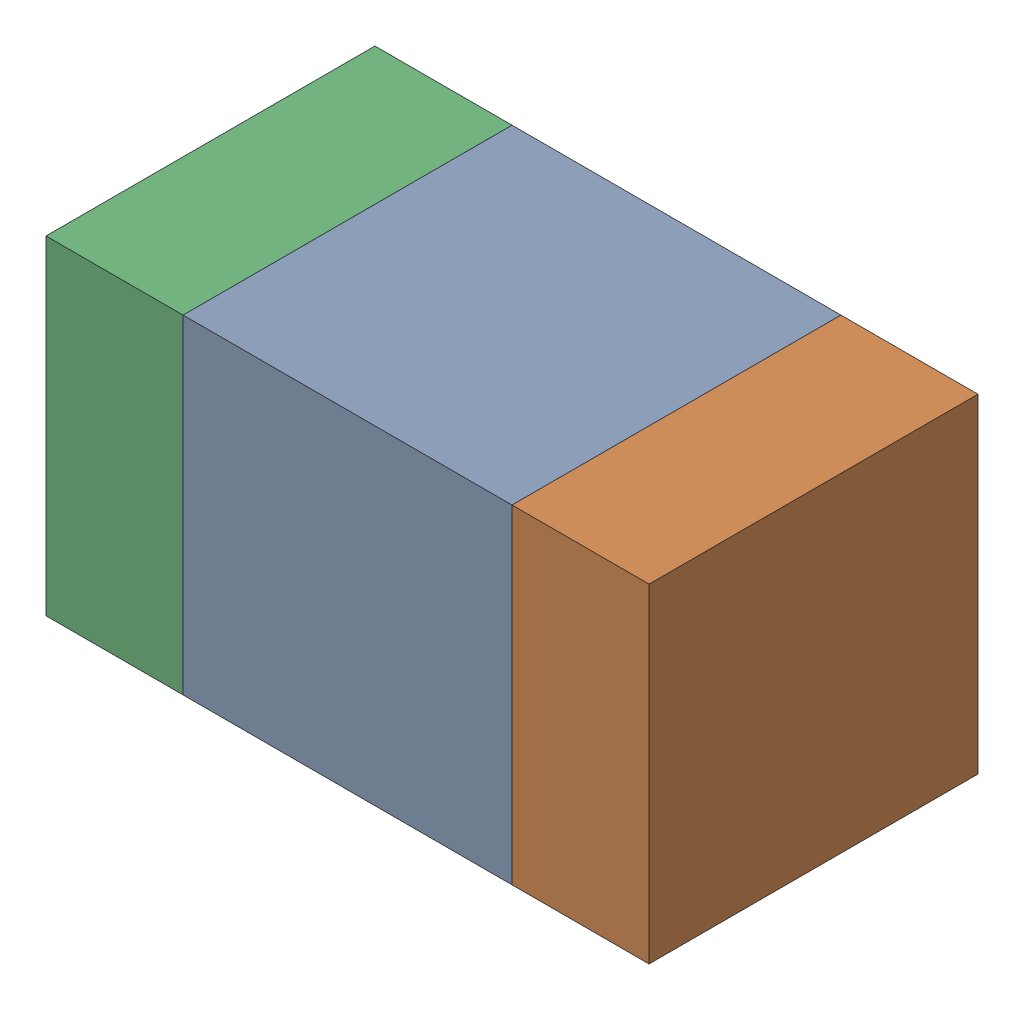
SolidWorks assembly C416PCB, configuration Default. Lengths in mm.
Overall size (1.1 0.6 0.6).
6 component instances, 2 part files, 0 mates.
Components (placement in the parent):
- 761606048-1: 761606048 [Default] at (125.1 100.5 0) size (0.6 0.6 0.6)
  - Extruded_9-1: Extruded_9 [Default] at origin size (0.6 0.6 0.6)
- 854785160-1: 854785160 [Default] at (125.525 100.5 0) size (0.25 0.6 0.6)
  - Extruded_19-1: Extruded_19 [Default] at origin size (0.25 0.6 0.6)
- 854785160-2: 854785160 [Default] at (124.675 100.5 0) size (0.25 0.6 0.6)
  - Extruded_19-1: Extruded_19 [Default] at origin size (0.25 0.6 0.6)
